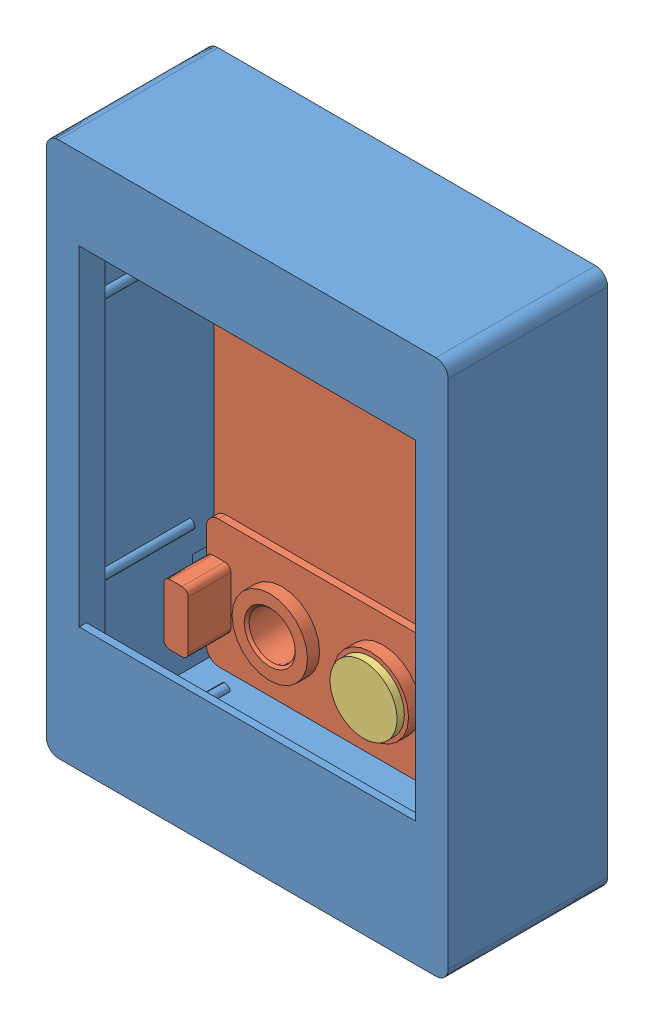
SolidWorks assembly 外壳装配体, configuration 默认. Lengths in mm.
Overall size (33 44 15.1).
3 component instances, 3 part files, 6 mates.
Components (placement in the parent):
- 屏幕前壳-1: 屏幕前壳 [默认] at origin size (33 44 13.1)
- 屏幕后壳-1: 屏幕后壳 [默认] at (31.05 2 2) x (-1 0 0) z (0 0 -1) size (30.6 40 5.5)
- 按钮D2.9-1: 按钮D2.9 [默认] at (16.55 7.2 3.6) x (-0.427393 0.904066 0) z (-0.904066 -0.427393 0) size (5.5 5.6 5.5)
Mates (geometry in assembly coordinates):
- 距离2: distance = 0.3 mm anti-aligned: plane of 屏幕前壳-1 through (1.7 42.3 11) normal (0 -1 0); plane of 屏幕后壳-1 through (31.05 42 0) normal (0 1 0)
- 平行1: parallel anti-aligned: plane of 屏幕前壳-1 through (31.3 42.3 11) normal (-1 0 0); plane of 屏幕后壳-1 through (31.05 2 0) normal (1 0 0)
- 距离1: distance = 0.25 mm anti-aligned: plane of 屏幕前壳-1 through (31.3 42.3 11) normal (-1 0 0); plane of 屏幕后壳-1 through (31.05 2 0) normal (1 0 0)
- LimitDistance1: limit distance = 0 mm aligned: plane of 屏幕后壳-1 through (31.05 2 0) normal (0 0 -1); plane of 屏幕前壳-1 through (0 0 0) normal (0 0 -1)
- 同心1: concentric anti-aligned: cylinder of 屏幕后壳-1 through (16.55 7.2 5.5) axis (0 0 -1) radius 1.9; cylinder of 按钮-1 through (16.55 7.2 -2) axis (0 0 1) radius 1.45
- 重合4: coincident anti-aligned: plane of 屏幕后壳-1 through (16.55 7.2 3) normal (0 0 1); plane of 按钮-1 through (16.55 7.2 3) normal (0 0 -1)
